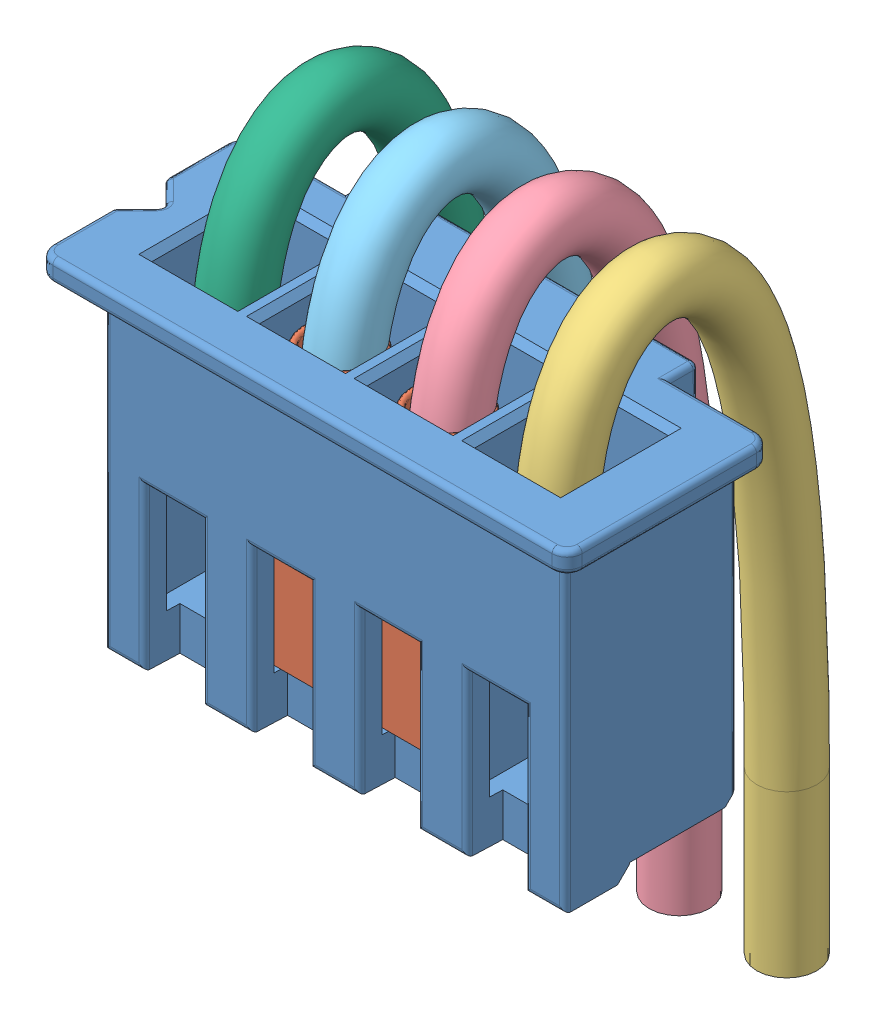
SolidWorks assembly JST Stepper connector assembly, configuration Default. Lengths in mm.
Overall size (12.3 15.75 8.2).
7 component instances, 6 part files, 15 mates.
Components (placement in the parent):
- JST XHP 4-1: JST XHP 4 [Default] at origin size (12.3 8 5.45)
- JSH XHP Contact Pin-3: JSH XHP Contact Pin [Default] at (1.25 1 0.25) size (2 6.61 2.5)
- JSH XHP Contact Pin-4: JSH XHP Contact Pin [Default] at (-1.25 1 0.25) size (2 6.61 2.5)
- Stepper wire Black-1: Stepper wire Black [Default] at (3.75 0 -0.0046) size (1.4 15.75 6.79)
- Stepper wire Green-1: Stepper wire Green [Default] at (1.25 0 -0.0046) size (1.4 15.75 6.79)
- Stepper wire Red-1: Stepper wire Red [Default] at (-1.25 0 -0.0046) size (1.4 15.75 6.79)
- Stepper wire Blue-1: Stepper wire Blue [Default] at (-3.75 0 -0.0046) size (1.4 15.75 6.79)
Mates (geometry in assembly coordinates):
- Coincident1: coincident aligned: plane of JST XHP 4-1 through (0 0 0) normal (0 0 1)
- Coincident2: coincident aligned: plane of JST XHP 4-1 through (0 0 0) normal (0 1 0)
- Coincident3: coincident aligned: plane of JST XHP 4-1 through (0 0 0) normal (1 0 0)
- Coincident8: coincident aligned: plane of JSH XHP Contact Pin-3 through (0.25 5.5 -1) normal (0 0 -1); plane of JSH XHP Contact Pin-4 through (-2.25 5.5 -1) normal (0 0 -1)
- Coincident14: coincident anti-aligned: plane of JST XHP 4-1 through (-2.25 1 -1) normal (1 0 0); plane of JSH XHP Contact Pin-4 through (-2.25 5.5 -1) normal (-1 0 0)
- Coincident15: coincident anti-aligned: plane of JST XHP 4-1 through (0.25 1 -1) normal (1 0 0); plane of JSH XHP Contact Pin-3 through (0.25 5.5 -1) normal (-1 0 0)
- Parallel1: parallel aligned: plane of JST XHP 4-1 through (5.35 7.5 -2) normal (1 0 0); plane of Stepper wire Black-1 through (3.75 0 -0.0046) normal (1 0 0)
- Parallel2: parallel aligned: plane of JST XHP 4-1 through (5.35 7.5 -2) normal (1 0 0); plane of Stepper wire Green-1 through (1.25 0 -0.0046) normal (1 0 0)
- Coincident21: coincident aligned: plane of Stepper wire Black-1 through (3.75 -4.9442 -4.7546) normal (0 -1 0); plane of Stepper wire Green-1 through (1.25 -4.9442 -4.7546) normal (0 -1 0)
- Concentric2: concentric aligned: circle of JSH XHP Contact Pin-3; circle of Stepper wire Green-1
- Parallel3: parallel aligned: plane of JST XHP 4-1 through (5.35 7.5 -2) normal (1 0 0); plane of Stepper wire Red-1 through (-1.25 0 -0.0046) normal (1 0 0)
- Coincident24: coincident aligned: plane of Stepper wire Green-1 through (1.25 -4.9442 -4.7546) normal (0 -1 0); plane of Stepper wire Red-1 through (-1.25 -4.9442 -4.7546) normal (0 -1 0)
- Concentric3: concentric aligned: circle of JSH XHP Contact Pin-4; circle of Stepper wire Red-1
- Parallel4: parallel aligned: plane of JST XHP 4-1 through (5.35 7.5 -2) normal (1 0 0); plane of Stepper wire Blue-1 through (-3.75 0 -0.0046) normal (1 0 0)
- Coincident27: coincident aligned: plane of Stepper wire Red-1 through (-1.25 -4.9442 -4.7546) normal (0 -1 0); plane of Stepper wire Blue-1 through (-3.75 -4.9442 -4.7546) normal (0 -1 0)
